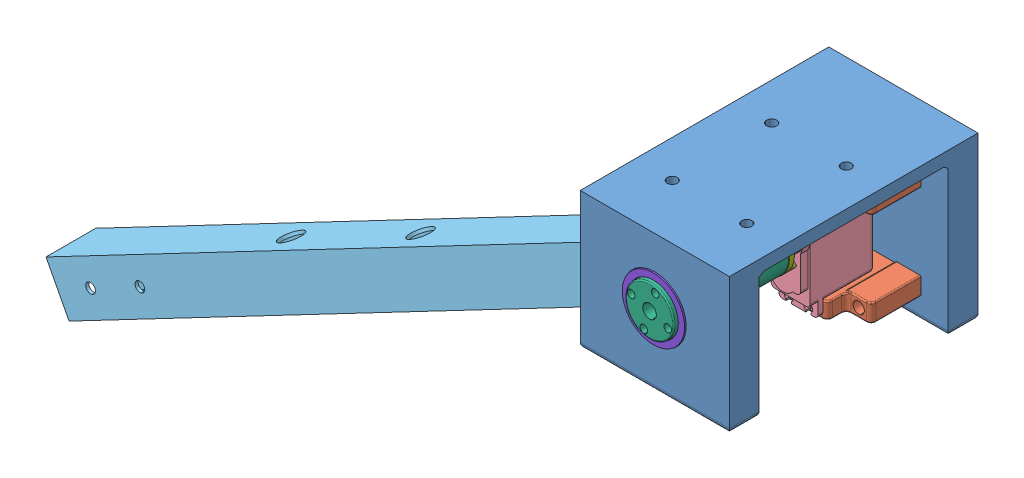
SolidWorks assembly MS-A-0013d-Gripper Arm, configuration Default. Lengths in mm.
Overall size (382.14 221.38 129.64).
17 component instances, 8 part files, 26 mates.
Components (placement in the parent):
- MS-P-0057-Gripper Arm Mount Version1-1: MS-P-0057-Gripper Arm Mount Version1 [Default] at (-52.2477 40.78 53.3156) x (0 0 1) z (0 1 0) size (127 76.2 82.55)
- MS-A-0013e-Shoulder Servo Mount Assembly-1: MS-A-0013e-Shoulder Servo Mount Assembly [Default] at (33.7787 -2.1863 -39.671) x (1 0 0) z (0 -1 0) size (48.26 52.81 57.28)
  - MS-P-0056-Shoulder Servo Mount-6: MS-P-0056-Shoulder Servo Mount [Default] at (-47.9263 -13.6934 17.7337) x (-1 0 0) z (0 1 0) size (48.26 9.14 35.05)
  - MS-P-0056-Shoulder Servo Mount-7: MS-P-0056-Shoulder Servo Mount [Default] at (-47.9263 -13.6934 -30.2663) x (1 0 0) z (0 1 0) size (48.26 9.14 35.05)
  - 97171A170_ HEAT-SET INSERT FOR PLASTIC-1: 97171A170_ HEAT-SET INSERT FOR PLASTIC [97171A170] at (-65.7063 -7.191 17.7337) x (0.915319 0 -0.402729) z (-0.402729 0 -0.915319) size (7.14 9.57 7.14)
  - 97171A170_ HEAT-SET INSERT FOR PLASTIC-2: 97171A170_ HEAT-SET INSERT FOR PLASTIC [97171A170] at (-30.1463 -7.191 17.7337) x (1 0 0) z (0 0 -1) size (7.14 9.57 7.14)
  - 97171A170_ HEAT-SET INSERT FOR PLASTIC-4: 97171A170_ HEAT-SET INSERT FOR PLASTIC [97171A170] at (-30.1463 -7.191 -30.2663) x (-1 0 0) z (0 0 1) size (7.14 9.57 7.14)
  - 97171A170_ HEAT-SET INSERT FOR PLASTIC-6: 97171A170_ HEAT-SET INSERT FOR PLASTIC [97171A170] at (-65.7063 -7.191 -30.2663) x (1 0 0) z (0 0 -1) size (7.14 9.57 7.14)
  - 97171A170_ HEAT-SET INSERT FOR PLASTIC-7: 97171A170_ HEAT-SET INSERT FOR PLASTIC [97171A170] at (-42.8463 8.1252 -30.2663) x (0.999861 0 -0.016687) z (0.016687 0 0.999861) size (7.14 9.57 7.14)
  - 97171A170_ HEAT-SET INSERT FOR PLASTIC-8: 97171A170_ HEAT-SET INSERT FOR PLASTIC [97171A170] at (-53.0063 8.1252 -30.2663) size (7.14 9.57 7.14)
  - 97171A170_ HEAT-SET INSERT FOR PLASTIC-9: 97171A170_ HEAT-SET INSERT FOR PLASTIC [97171A170] at (-42.8463 8.1252 17.7337) size (7.14 9.57 7.14)
  - 97171A170_ HEAT-SET INSERT FOR PLASTIC-10: 97171A170_ HEAT-SET INSERT FOR PLASTIC [97171A170] at (-53.0063 8.1252 17.7337) size (7.14 9.57 7.14)
  - MS-C-0032-Gripper Shoulder Servo-1: MS-C-0032-Gripper Shoulder Servo [Default] at (-48.0063 17.0406 -6.2663) x (0 0 -1) z (1 0 0) size (53.2 43.5 20)
- MS-P-0054-Box Tubing-1: MS-P-0054-Box Tubing [Default] at (-37.2902 1.9994 7.6336) x (0 0 -1) z (-0.885829 -0.464012 0) size (25.4 25.4 355.6)
- MS-P-0058-Shoulder L Joint-1: MS-P-0058-Shoulder L Joint [Default] at (-14.2277 14.08 8.3321) x (0 0 -1) z (-0.885829 -0.464012 0) size (58.74 26.61 88.65)
- 525130.step-1: 525130.step [Default] at (-14.2277 14.08 -9.1304) x (0.464012 -0.885829 0) z (-0.885829 -0.464012 0) size (25.39 6.35 25.39)
- MS-C-0028-Servo Arm Bushing-1: MS-C-0028-Servo Arm Bushing [2934T25] at (-14.2277 14.08 34.9006) x (1 0 0) z (0 -1 0) size (38.1 19.05 38.1)
Mates (geometry in assembly coordinates):
- Distance1: distance = 6.35 mm anti-aligned: plane of MS-P-0047 - Gripper Arm Mount-1 through (95.6161 2.1794 54.1355) normal (0 0 -1); plane of GripperArm-1 through (52.9892 28.9852 43.023) normal (0 0 1)
- Concentric2: concentric aligned: cylinder of GripperArm-1 through (57.5161 21.2294 36.673) axis (0 0 1) radius 3.9688; cylinder of 6389K231_LIGHT DUTY DRY-RUNNING SLEEVE BEARING-1 through (19.4161 14.8794 63.9267) axis (0 0 1) radius 4.7625
- Coincident3: coincident anti-aligned: plane of MS-P-0047 - Gripper Arm Mount-1 through (23.9523 47.13 53.3156) normal (0 0 1); plane of 6389K231_LIGHT DUTY DRY-RUNNING SLEEVE BEARING-2 through (19.4161 14.8794 69.3755) normal (0 0 -1)
- Concentric4: concentric anti-aligned: cylinder of 6389K231_LIGHT DUTY DRY-RUNNING SLEEVE BEARING-2 through (19.4161 14.8794 63.0255) axis (0 0 1) radius 3.175; cylinder of 90325A181_18-8 STAINLESS STEEL PRECISION SHOULDER SCREW-1 through (14.5574 87.2469 34.4811) axis (0 0 -1) radius 3.175
- Coincident4: coincident anti-aligned: plane of 6389K231_LIGHT DUTY DRY-RUNNING SLEEVE BEARING-2 through (19.4161 14.8794 70.963) normal (0 0 1); plane of 90325A181_18-8 STAINLESS STEEL PRECISION SHOULDER SCREW-1 through (14.5574 82.4844 59.8811) normal (0 0 -1)
- Concentric5: concentric anti-aligned: cylinder of 90325A181_18-8 STAINLESS STEEL PRECISION SHOULDER SCREW-1 through (14.5574 87.2469 34.4811) axis (0 0 -1) radius 1.6764; circle of 90631A011_LOW-STRENGTH STEEL NYLON-INSERT LOCKNUT-1
- Coincident5: coincident anti-aligned: plane of MS-P-0047 - Gripper Arm Mount-1 through (23.9523 -22.72 38.0756) normal (0 0 -1); plane of 90631A011_LOW-STRENGTH STEEL NYLON-INSERT LOCKNUT-1 through (19.9239 88.4479 56.6755) normal (0 0 1)
- Concentric6: concentric aligned: cylinder of GripperArm-1 through (57.5161 21.2294 36.673) axis (0 0 1) radius 3.9688; cylinder of 98002A930_STEEL BINDING BARRELS AND SCREWS-1 through (19.4161 14.8794 61.9826) axis (0 0 1) radius 3.175
- Coincident6: coincident anti-aligned: plane of GripperArm-1 through (52.9892 28.9852 36.673) normal (0 0 -1); plane of 98002A930_STEEL BINDING BARRELS AND SCREWS-1 through (19.4161 14.8794 70.9629) normal (0 0 1)
- Coincident13: coincident anti-aligned: plane of MS-P-0047 - Gripper Arm Mount-1 through (23.9523 -35.42 -58.4444) normal (0 0 1); plane of MS-A-0013 - Gripper Arm-1/MS-P-0048 - Servo Mount Piece-3 through (57.5161 40.2794 -42.3845) normal (0 0 -1)
- Concentric12: concentric anti-aligned: cylinder of MS-P-0047 - Gripper Arm Mount-1 through (3.6323 28.08 53.3166) axis (0 0 -1) radius 2.54; cylinder of MS-A-0013 - Gripper Arm-1/MS-P-0048 - Servo Mount Piece-3 through (76.5661 40.2794 -42.3845) axis (0 0 1) radius 2.54
- Parallel1: parallel anti-aligned: cylinder of MS-P-0047 - Gripper Arm Mount-1 through (-31.9277 -19.92 53.3166) axis (0 0 -1) radius 2.54; cylinder of MS-A-0013 - Gripper Arm-1/MS-P-0048 - Servo Mount Piece-4 through (38.6261 -10.4206 -42.3845) axis (0 0 1) radius 2.54
- Concentric15: concentric anti-aligned: cylinder of MS-P-0047 - Gripper Arm Mount-1 through (-31.9277 28.08 53.3166) axis (0 0 -1) radius 2.54; cylinder of MS-A-0013 - Gripper Arm-1/MS-P-0048 - Servo Mount Piece-3 through (38.4661 40.2794 -42.3845) axis (0 0 1) radius 2.54
- Concentric16: concentric anti-aligned: circle of MS-P-0049- Gripper Arm Servo Horn Mount-1; circle of 525130.step-1
- Coincident15: coincident anti-aligned: plane of MS-P-0058-Shoulder L Joint-1 through (-14.2277 14.08 -2.7804) normal (0 0 -1); plane of 525130.step-1 through (-14.2277 14.08 -2.7804) normal (0 0 1)
- Concentric18: concentric anti-aligned: circle of MS-A-0013 - Gripper Arm-1/11886-2/11886_top-1; circle of 525130.step-1
- Coincident16: coincident anti-aligned: plane of MS-A-0013 - Gripper Arm-1/11886-2/11886_top-1 through (63.8475 25.5794 10.7295) normal (0 0 1); plane of 525130.step-1 through (-14.2277 14.08 -5.8284) normal (0 0 -1)
- Concentric20: concentric anti-aligned: circle of MS-A-0013 - Gripper Arm-1/MS-P-0048 - Servo Mount Piece-6; circle of MS-P-0047 - Gripper Arm Mount-1
- Coincident17: coincident anti-aligned: plane of MS-P-0047 - Gripper Arm Mount-1 through (23.9523 -35.42 -58.4444) normal (0 0 1); plane of MS-A-0013 - Gripper Arm-1/MS-P-0048 - Servo Mount Piece-6 through (-14.1477 -19.92 -58.4444) normal (0 0 -1)
- Distance2: distance = 0.635 mm anti-aligned: plane of GripperArmBoxTubing-1 through (-37.2902 1.9994 7.6336) normal (0.885829 0.464012 0); plane of MS-P-0049- Gripper Arm Servo Horn Mount-1 through (-36.7277 2.2941 21.0321) normal (-0.885829 -0.464012 0)
- Coincident20: coincident anti-aligned: plane of MS-P-0047 - Gripper Arm Mount-1 through (23.9523 -22.72 38.0756) normal (0 0 -1); plane of MS-C-0028- Servo Arm Bushing-1 through (-14.2277 14.08 38.0756) normal (0 0 1)
- Concentric23: concentric aligned: cylinder of MS-P-0058-Shoulder L Joint-1 through (-14.2277 14.08 21.0321) axis (0 0 -1) radius 12.446; cylinder of MS-C-0028- Servo Arm Bushing-1 through (-14.2277 14.08 53.9506) axis (0 0 -1) radius 15.9004
- Concentric24: concentric aligned: circle of MS-A-0013 - Gripper Arm-1/MS-C-0029 - D956-WP Servo-1; circle of 525130.step-1
- Coincident21: coincident anti-aligned: plane of MS-A-0013 - Gripper Arm-1/MS-C-0029 - D956-WP Servo-1 through (-14.2277 14.08 -9.1304) normal (0 0 1); plane of 525130.step-1 through (-14.2277 14.08 -9.1304) normal (0 0 -1)
- Width1: width anti-aligned: plane of MS-P-0058-Shoulder L Joint-1 through (-86.56 -12.0527 18.0476) normal (0 0 1); plane of MS-P-0058-Shoulder L Joint-1 through (-14.2277 14.08 -2.7804) normal (0 0 -1); plane of MS-P-0054-Box Tubing-1 through (-346.398 -174.2533 -5.0664) normal (0 0 -1); plane of MS-P-0054-Box Tubing-1 through (-346.398 -174.2533 20.3336) normal (0 0 1)
- Width2: width aligned: plane of MS-P-0058-Shoulder L Joint-1 through (-86.56 -12.0527 -2.7804) normal (-0.464012 0.885829 0); plane of MS-P-0058-Shoulder L Joint-1 through (-76.8956 -30.5028 -2.7804) normal (0.464012 -0.885829 0); plane of MS-P-0054-Box Tubing-1 through (-358.1839 -151.7532 20.3336) normal (-0.464012 0.885829 0); plane of MS-P-0054-Box Tubing-1 through (-346.398 -174.2533 20.3336) normal (0.464012 -0.885829 0)
